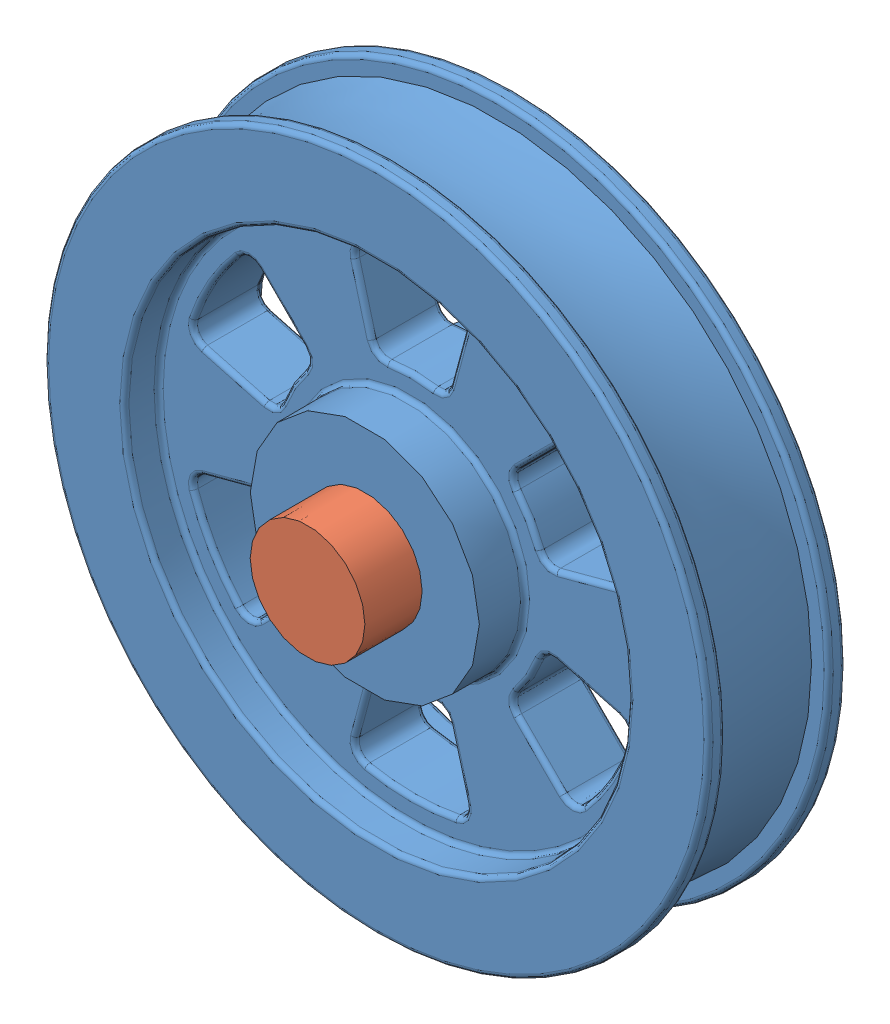
SolidWorks assembly Wheel Shaft Assembly, configuration Default. Lengths in mm.
Overall size (368.3 368.3 152.4).
2 component instances, 2 part files, 2 mates.
Components (placement in the parent):
- wheel-1: wheel [Default] at origin size (368.3 368.3 88.9)
- Shaft-1: Shaft [Default] at origin size (63.6 63.6 152.4)
Mates (geometry in assembly coordinates):
- Concentric1: concentric anti-aligned: cylinder of wheel-1 through (0 0 130.7747) axis (0 0 1) radius 31.75; cylinder of Shaft-1 through (0 0 76.2) axis (0 0 -1) radius 31.8021
- Distance3: distance = 31.75 mm aligned: plane of wheel-1 through (0 31.75 -44.45) normal (0 0 -1); plane of Shaft-1 through (0 0 -76.2) normal (0 0 -1)
